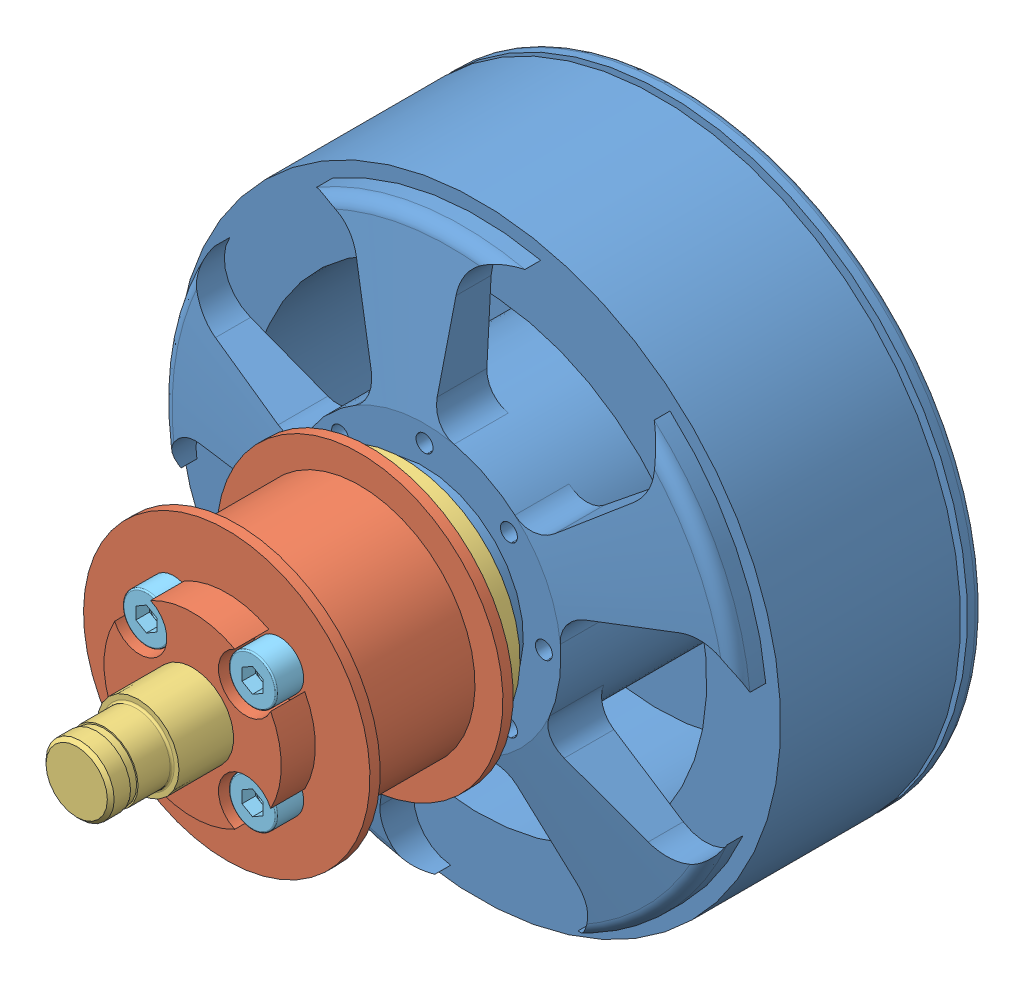
SolidWorks assembly Short Motor Assembly, configuration Default. Lengths in mm.
Overall size (125.3 125.3 91).
11 component instances, 5 part files, 17 mates.
Components (placement in the parent):
- T-Motor U10 KV80-1: T-Motor U10 KV80 [Default] at (150.6204 137.0959 116.3778) x (0.707107 0.707107 0) z (0 0 1) size (88.6 88.6 43)
- Timing Belt Pulley-1: Timing Belt Pulley [Default] at (150.6204 137.0959 164.3778) x (0.707107 0.707107 0) z (0 0 -1) size (42 42 26)
- Motor Shaft Short-1: Motor Shaft Short [Default] at (150.6204 137.0959 159.3778) x (0 1 0) z (0 0 1) size (34 34 68)
- ISO 10642 - M4 x 12 - 12C-9: ISO 10642 - M4 x 12 - 12C [ISO 10642 - M4 x 12 - 12C] at (139.1204 137.0959 164.3578) x (0 0 -1) z (1 -0.000264 0) size (12 7.53 7.53)
- ISO 10642 - M4 x 12 - 12C-10: ISO 10642 - M4 x 12 - 12C [ISO 10642 - M4 x 12 - 12C] at (150.6204 148.5959 164.3578) x (0 0 -1) z (1 0 0) size (12 7.53 7.53)
- ISO 10642 - M4 x 12 - 12C-11: ISO 10642 - M4 x 12 - 12C [ISO 10642 - M4 x 12 - 12C] at (162.1204 137.0959 164.3578) x (0 0 -1) z (1 0 0) size (12 7.53 7.53)
- ISO 4762 M4 x 25 - 25C-2: ISO 4762 M4 x 25 - 25C [PreviewCfg] at (142.8422 144.8741 189.3778) x (0 0 -1) z (1 0 0) size (29 7 7)
- ISO 4762 M4 x 25 - 25C-4: ISO 4762 M4 x 25 - 25C [ISO 4762 M4 x 25 - 25C] at (158.3986 129.3178 189.3778) x (0 0 -1) z (1 0 0) size (29 7 7)
- ISO 4762 M4 x 25 - 25C-6: ISO 4762 M4 x 25 - 25C [ISO 4762 M4 x 25 - 25C] at (158.3986 144.8741 189.3778) x (0 0 -1) z (1 0 0) size (29 7 7)
- ISO 10642 - M4 x 12 - 12C-12: ISO 10642 - M4 x 12 - 12C [ISO 10642 - M4 x 12 - 12C] at (150.6204 125.5959 164.3578) x (0 0 -1) z (1 0 0) size (12 7.53 7.53)
- ISO 4762 M4 x 25 - 25C-8: ISO 4762 M4 x 25 - 25C [ISO 4762 M4 x 25 - 25C] at (142.8422 129.3178 189.3778) x (0 0 -1) z (1 0 0) size (29 7 7)
Mates (geometry in assembly coordinates):
- Concentric36: concentric: cylinder of T-Motor U10 KV80-1 through (150.6204 137.0959 134.3778) axis (0 0 1) radius 5.25; cylinder of Motor Shaft Short-1 through (150.6204 137.0959 139.3778) axis (0 0 1) radius 5.2
- Concentric37: concentric: cylinder of T-Motor U10 KV80-1 through (139.1204 137.0959 159.3778) axis (0 0 1) radius 1.65; cylinder of Motor Shaft Short-1 through (139.1204 137.0959 164.3778) axis (0 0 1) radius 2
- Coincident21: coincident: plane of T-Motor U10 KV80-1 through (140.3673 147.349 159.3778) normal (0 0 1); plane of Motor Shaft Short-1 through (150.6204 137.0959 159.3778) normal (0 0 -1)
- Coincident27: coincident: plane of Timing Belt Pulley-1 through (165.4696 122.2467 164.3778) normal (0 0 -1); plane of Motor Shaft Short-1 through (150.6204 137.0959 164.3778) normal (0 0 1)
- Coincident28: coincident: plane of Timing Belt Pulley-1 through (159.8128 127.9035 185.3778) normal (0 0 1); plane of ISO 4762 M4 x 25 - 25C-2 through (142.8422 148.3741 185.3778) normal (0 0 -1)
- Coincident291: coincident: plane of Timing Belt Pulley-1 through (159.8128 127.9035 185.3778) normal (0 0 1); plane of ISO 4762 M4 x 25 - 25C-4 through (158.3986 132.8178 185.3778) normal (0 0 -1)
- Coincident301: coincident: plane of Timing Belt Pulley-1 through (159.8128 127.9035 185.3778) normal (0 0 1); plane of ISO 4762 M4 x 25 - 25C-6 through (158.3986 148.3741 185.3778) normal (0 0 -1)
- Coincident311: coincident: plane of Timing Belt Pulley-1 through (159.8128 127.9035 185.3778) normal (0 0 1); plane of ISO 4762 M4 x 25 - 25C-8 through (142.8422 132.8178 185.3778) normal (0 0 -1)
- Concentric4604: concentric: cylinder of Timing Belt Pulley-1 through (150.6204 137.0959 164.3778) axis (0 0 1) radius 6; cylinder of Motor Shaft Short-1 through (150.6204 137.0959 139.3778) axis (0 0 -1) radius 6
- Concentric4648779: concentric: cylinder of Timing Belt Pulley-1 through (142.8422 144.8741 190.3778) axis (0 0 1) radius 2; cylinder of ISO 4762 M4 x 25 - 25C-2 through (142.8422 144.8741 221.1278) axis (0 0 1) radius 2
- Concentric4648780: concentric: cylinder of Timing Belt Pulley-1 through (142.8422 129.3178 190.3778) axis (0 0 1) radius 2; cylinder of ISO 4762 M4 x 25 - 25C-8 through (142.8422 129.3178 221.1278) axis (0 0 1) radius 2
- Concentric4648781: concentric: cylinder of Timing Belt Pulley-1 through (158.3986 144.8741 190.3778) axis (0 0 1) radius 2; cylinder of ISO 4762 M4 x 25 - 25C-6 through (158.3986 144.8741 221.1278) axis (0 0 1) radius 2
- Concentric4648782: concentric: cylinder of Timing Belt Pulley-1 through (158.3986 129.3178 190.3778) axis (0 0 1) radius 2; cylinder of ISO 4762 M4 x 25 - 25C-4 through (158.3986 129.3178 221.1278) axis (0 0 1) radius 2
- Coincident22: coincident: cone of Motor Shaft Short-1 through (139.1204 137.0959 164.3778) axis (0 0 -1); cone of ISO 10642 - M4 x 12 - 12C-9 through (139.1204 137.0959 163.6428) axis (0 0 -1)
- Coincident231: coincident: cone of Motor Shaft Short-1 through (150.6204 148.5959 164.3778) axis (0 0 -1); cone of ISO 10642 - M4 x 12 - 12C-10 through (150.6204 148.5959 163.6428) axis (0 0 -1)
- Coincident241: coincident: cone of Motor Shaft Short-1 through (150.6204 125.5959 164.3778) axis (0 0 -1); cone of ISO 10642 - M4 x 12 - 12C-12 through (150.6204 125.5959 163.6428) axis (0 0 -1)
- Coincident251: coincident: cone of Motor Shaft Short-1 through (162.1204 137.0959 164.3778) axis (0 0 -1); cone of ISO 10642 - M4 x 12 - 12C-11 through (162.1204 137.0959 163.6428) axis (0 0 -1)
